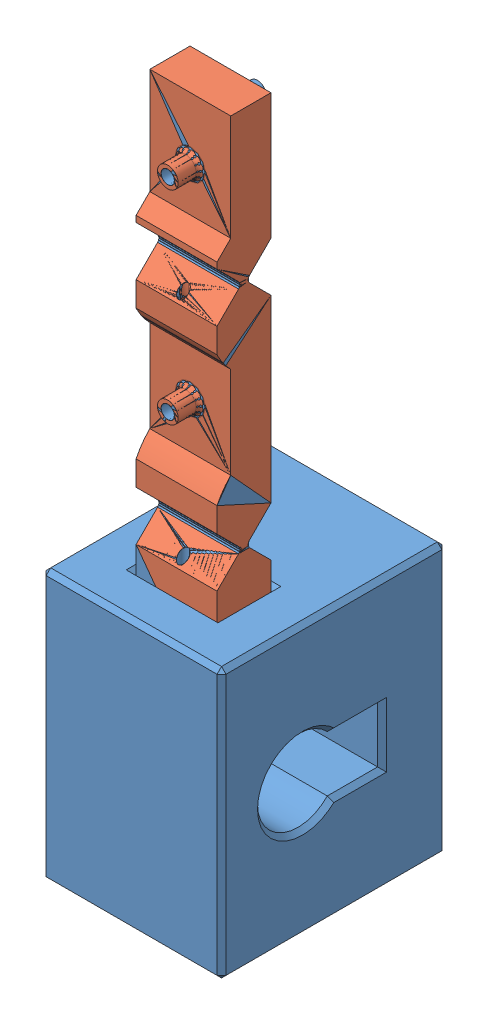
SolidWorks assembly TestRigAssem, configuration Default. Lengths in mm.
Overall size (50.4 155 50).
6 component instances, 5 part files, 11 mates.
Components (placement in the parent):
- FingerTestMount-1: FingerTestMount [Default] at origin size (40 155 50)
- MiddleFinger1.2-2: MiddleFinger1.2 [Default] at origin size (18 114.5 13.95)
- AGFRC Micro Servo-1: AGFRC Micro Servo [Default] at (-30.4 -41 3.5) x (0 1 0) z (0 0 -1) size (12 31.6 32)
- FingerPulley-1: FingerPulley [Default] at (0 -41 -2) x (1 0 0) z (0 0.628595 -0.777733) size (4 14 14)
- New TMAG5273-1: New TMAG5273 [Default] at (-150.195 125.175 -1.6) size (12.4 10.5 3.2)
- New TMAG5273-2: New TMAG5273 [Default] at (-150.195 170.425 -1.6) size (12.4 10.5 3.2)
Mates (geometry in assembly coordinates):
- Width1: width anti-aligned: plane of FingerTestMount-1 through (20 -34.8 0) normal (0 -1 0); plane of FingerTestMount-1 through (20 -47.2 0) normal (0 1 0); plane of AGFRC Micro Servo-1 through (-30.4 -35 3.5) normal (0 1 0); plane of AGFRC Micro Servo-1 through (-30.4 -47 3.5) normal (0 -1 0)
- Width2: width aligned: plane of FingerTestMount-1 through (-55.0657 -34.8 -24.4) normal (0 0 1); plane of FingerTestMount-1 through (-55.0657 -34.8 8.4) normal (0 0 -1); plane of AGFRC Micro Servo-1 through (-30.4 -35 3.5) normal (0 0 1); plane of AGFRC Micro Servo-1 through (-30.4 -35 -19.5) normal (0 0 -1)
- Coincident1: coincident anti-aligned: plane of FingerTestMount-1 through (-8.5 0 0) normal (-1 0 0); plane of AGFRC Micro Servo-1 through (-8.5 -35 3.5) normal (1 0 0)
- Concentric1: concentric aligned: cylinder of AGFRC Micro Servo-1 through (1.2 -41 -2) axis (-1 0 0) radius 2.45; cylinder of FingerPulley-1 through (2 -41 -2) axis (-1 0 0) radius 2.6
- Coincident2: coincident anti-aligned: plane of AGFRC Micro Servo-1 through (-2 -41 -2) normal (1 0 0); plane of FingerPulley-1 through (-2 -41 -2) normal (-1 0 0)
- Coincident3: coincident: line of ? through (0 25.5 7.95) axis (0 0 -1); point of New TMAG5273-1
- Coincident4: coincident anti-aligned: plane of MiddleFinger1.2-2 through (0 64.75 0) normal (0 0 -1); plane of New TMAG5273-1 through (-0.195 21.925 0) normal (0 0 1)
- Parallel1: parallel aligned: plane of MiddleFinger1.2-2 through (-9 84.5 2.95) normal (0 1 0); plane of New TMAG5273-1 through (6.005 27.175 -1.6) normal (0 1 0)
- Coincident5: coincident: line of MiddleFinger1.2-2 through (0 70.75 7.95) axis (0 0 -1)
- Coincident6: coincident anti-aligned: plane of MiddleFinger1.2-2 through (-5 48 0) normal (0 0 -1); plane of New TMAG5273-2 through (-0.195 67.175 0) normal (0 0 1)
- Parallel2: parallel aligned: plane of MiddleFinger1.2-2 through (-9 84.5 2.95) normal (0 1 0); plane of New TMAG5273-2 through (6.005 72.425 -1.6) normal (0 1 0)
